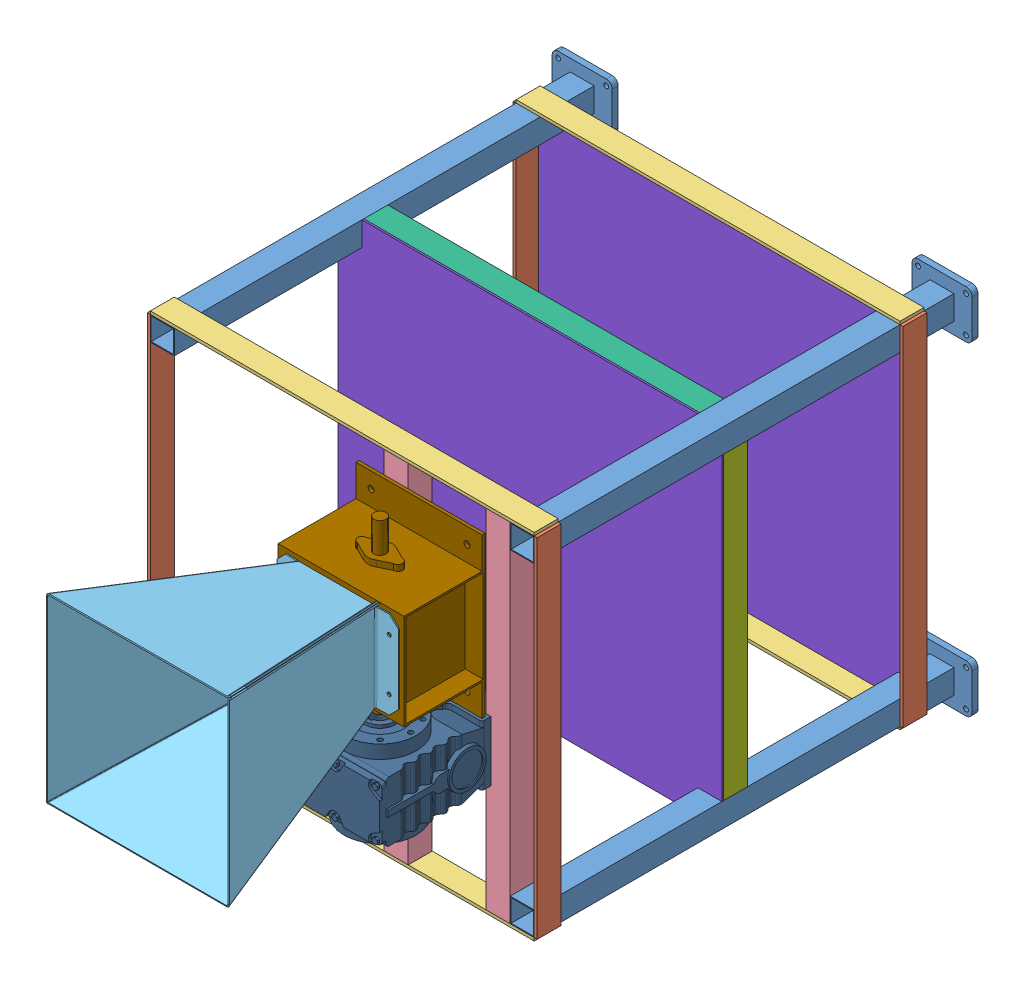
SolidWorks assembly Assemblage1, configuration Défaut. Lengths in mm.
Overall size (700 635.38 1223.8).
25 component instances, 10 part files, 63 mates.
Components (placement in the parent):
- PIED-1: PIED [Défaut] at (-115.1422 36.712 1420) x (-1 0 0) z (0 0 -1) size (100 80 710)
- PIED-2: PIED [Défaut] at (484.8578 36.712 1420) x (-1 0 0) z (0 0 -1) size (100 80 710)
- PIED-3: PIED [Défaut] at (-115.1422 -503.288 1420) x (-1 0 0) z (0 0 -1) size (100 80 710)
- PIED-4: PIED [Défaut] at (484.8578 -503.288 1420) x (-1 0 0) z (0 0 -1) size (100 80 710)
- RENFORT_largeur-1: RENFORT_largeur [Défaut] at (509.8578 -233.288 790) x (0 1 0) z (-1 0 0) size (580 40 5)
- RENFORT_largeur-2: RENFORT_largeur [Défaut] at (509.8578 -233.288 1400) x (0 1 0) z (-1 0 0) size (580 40 5)
- RENFORT_largeur-3: RENFORT_largeur [Défaut] at (-140.1422 -233.288 790) x (0 -1 0) z (1 0 0) size (580 40 5)
- RENFORT_largeur-4: RENFORT_largeur [Défaut] at (-140.1422 -233.288 1400) x (0 -1 0) z (1 0 0) size (580 40 5)
- RENFORT_longueur-1: RENFORT_longueur [Défaut] at (184.8578 61.712 790) x (1 0 0) z (0 -1 0) size (640 40 5)
- RENFORT_longueur-2: RENFORT_longueur [Défaut] at (184.8578 61.712 1400) x (1 0 0) z (0 -1 0) size (640 40 5)
- RENFORT_longueur-3: RENFORT_longueur [Défaut] at (184.8578 -528.288 790) x (1 0 0) z (0 1 0) size (640 40 5)
- RENFORT_longueur-4: RENFORT_longueur [Défaut] at (184.8578 -528.288 1400) x (1 0 0) z (0 1 0) size (640 40 5)
- 580mm 40x40-1: 580mm 40x40 [Défaut] at (274.8578 -523.288 1400) x (0 0 1) z (0 1 0) size (40 40 580)
- 580mm 40x40-2: 580mm 40x40 [Défaut] at (444.8578 -523.288 1400) x (-1 0 0) z (0 1 0) size (40 40 580)
- Trémie Assemblée-1: Trémie Assemblée [Default] at (161.1073 -328.8776 1561.0107) x (0.999994 -0.00237 -0.00261) z (0.002608 -0.000629 0.999996) size (322.31 323.64 336.67)
  - Trémie-1: Trémie [Défaut] at (196.1744 257.0221 41.9114) size (320.13 321.45 336.3)
  - Trémie-2: Trémie [Défaut] at (192.2926 260.8978 41.7629) x (-0.999997 -0.00237 -0.000538) z (-0.000539 0.000628 1) size (320.13 321.45 336.3)
- 560mm 40x40-1: 560mm 40x40 [Défaut] at (-95.1422 -503.288 1083.9985) x (0 0 -1) z (1 0 0) size (40 40 560)
- 560mm 40x40-2: 560mm 40x40 [Défaut] at (-95.1422 36.712 1083.9985) x (0 0 -1) z (1 0 0) size (40 40 560)
- 500mm 40x40-1: 500mm 40x40 [Défaut] at (484.8578 -483.288 1083.9985) x (1 0 0) z (0 1 0) size (40 40 500)
- 500mm 40x40-2: 500mm 40x40 [Défaut] at (-115.1422 16.712 1083.9985) x (1 0 0) z (0 -1 0) size (40 40 500)
- WorkbenchV-1: WorkbenchV [Défaut] at (254.8578 -243.288 770) x (0 1 0) z (0 0 1) size (580 640 3)
- WorkbenchV-2: WorkbenchV [Défaut] at (114.8578 -223.288 1103.9985) x (0 -1 0) z (0 0 1) size (580 640 3)
- Shredder-2: Shredder [Défaut] at (359.8578 -70.788 1597) x (0 1 0) z (0 0 -1) size (280 210 135)
- SEW SA57DZ71C4-2: SEW SA57DZ71C4 [Défaut] at (359.8578 -217.9826 1532) x (-1 0 0) z (0 0 1) size (393.09 196.49 188.11)
Mates (geometry in assembly coordinates):
- Coïncidente1: coincident aligned: plane of PIED-1 through (-75.1422 6.712 710) normal (0 0 -1); plane of PIED-3 through (-75.1422 -533.288 710) normal (0 0 -1)
- Coïncidente2: coincident aligned: plane of PIED-1 through (-75.1422 6.712 710) normal (0 0 -1); plane of PIED-4 through (524.8578 -533.288 710) normal (0 0 -1)
- Coïncidente4: coincident aligned: plane of PIED-2 through (524.8578 6.712 710) normal (0 0 -1); plane of PIED-4 through (524.8578 -533.288 710) normal (0 0 -1)
- Coïncidente5: coincident anti-aligned: plane of PIED-3 through (-95.1422 -523.288 720) normal (0 -1 0); plane of RENFORT_longueur-4 through (184.8578 -523.288 1400) normal (0 1 0)
- Coïncidente6: coincident: plane of PIED-4 through (504.8578 -523.288 720) normal (1 0 0); line of RENFORT_longueur-4 through (504.8578 -523.288 1420) axis (0 0 -1)
- Coïncidente7: coincident aligned: plane of PIED-3 through (-95.1422 -523.288 720) normal (0 -1 0); plane of PIED-4 through (504.8578 -523.288 720) normal (0 -1 0)
- Coïncidente8: coincident aligned: plane of PIED-3 through (-135.1422 -523.288 720) normal (-1 0 0); plane of RENFORT_longueur-4 through (-135.1422 -523.288 1420) normal (-1 0 0)
- Coïncidente9: coincident anti-aligned: plane of PIED-3 through (-95.1422 -523.288 720) normal (0 -1 0); plane of RENFORT_longueur-3 through (184.8578 -523.288 790) normal (0 1 0)
- Coïncidente10: coincident: plane of PIED-4 through (504.8578 -523.288 720) normal (1 0 0); line of RENFORT_longueur-3 through (504.8578 -523.288 810) axis (0 0 -1)
- Coïncidente11: coincident aligned: plane of PIED-4 through (484.8578 -503.288 1420) normal (0 0 1); plane of RENFORT_longueur-4 through (-135.1422 -523.288 1420) normal (0 0 1)
- Distance1: distance = 50 mm anti-aligned: plane of PIED-4 through (524.8578 -533.288 720) normal (0 0 1); plane of RENFORT_longueur-3 through (-135.1422 -523.288 770) normal (0 0 -1)
- Coïncidente13: coincident anti-aligned: plane of PIED-2 through (504.8578 56.712 720) normal (0 1 0); plane of RENFORT_longueur-1 through (184.8578 56.712 790) normal (0 -1 0)
- Coïncidente14: coincident anti-aligned: plane of PIED-2 through (504.8578 56.712 720) normal (0 1 0); plane of RENFORT_longueur-2 through (184.8578 56.712 1400) normal (0 -1 0)
- Coïncidente15: coincident aligned: plane of PIED-2 through (504.8578 16.712 720) normal (1 0 0); plane of RENFORT_longueur-2 through (504.8578 56.712 1380) normal (1 0 0)
- Coïncidente16: coincident aligned: plane of PIED-2 through (504.8578 16.712 720) normal (1 0 0); plane of RENFORT_longueur-1 through (504.8578 56.712 770) normal (1 0 0)
- Coïncidente17: coincident aligned: plane of PIED-2 through (504.8578 16.712 720) normal (1 0 0); plane of PIED-4 through (504.8578 -523.288 720) normal (1 0 0)
- Coïncidente18: coincident: plane of PIED-1 through (-135.1422 16.712 720) normal (-1 0 0); line of PIED-3 through (-135.1422 -523.288 720) axis (0 0 1)
- Coïncidente19: coincident aligned: plane of RENFORT_longueur-1 through (-135.1422 56.712 810) normal (0 0 1); plane of RENFORT_longueur-3 through (-135.1422 -523.288 810) normal (0 0 1)
- Coïncidente20: coincident: plane of PIED-2 through (484.8578 36.712 1420) normal (0 0 1); line of RENFORT_longueur-2 through (504.8578 61.712 1420) axis (-1 0 0)
- Coïncidente21: coincident anti-aligned: plane of PIED-1 through (-95.1422 56.712 720) normal (0 1 0); plane of RENFORT_longueur-2 through (184.8578 56.712 1400) normal (0 -1 0)
- Coïncidente22: coincident anti-aligned: plane of PIED-1 through (-135.1422 16.712 720) normal (-1 0 0); plane of RENFORT_largeur-3 through (-135.1422 -233.288 790) normal (1 0 0)
- Coïncidente23: coincident aligned: plane of PIED-1 through (-95.1422 56.712 720) normal (0 1 0); plane of RENFORT_largeur-3 through (-135.1422 56.712 810) normal (0 1 0)
- Distance2: distance = 50 mm anti-aligned: plane of RENFORT_largeur-3 through (-135.1422 56.712 770) normal (0 0 -1); plane of PIED-1 through (-75.1422 6.712 720) normal (0 0 1)
- Coïncidente25: coincident aligned: plane of PIED-3 through (-95.1422 -523.288 720) normal (0 -1 0); plane of RENFORT_largeur-3 through (-135.1422 -523.288 810) normal (0 -1 0)
- Coïncidente26: coincident anti-aligned: plane of PIED-1 through (-135.1422 16.712 720) normal (-1 0 0); plane of RENFORT_largeur-4 through (-135.1422 -233.288 1400) normal (1 0 0)
- Coïncidente27: coincident aligned: plane of PIED-1 through (-115.1422 36.712 1420) normal (0 0 1); plane of RENFORT_largeur-4 through (-135.1422 56.712 1420) normal (0 0 1)
- Coïncidente28: coincident aligned: plane of PIED-2 through (504.8578 56.712 720) normal (0 1 0); plane of RENFORT_largeur-4 through (-135.1422 56.712 1420) normal (0 1 0)
- Coïncidente29: coincident anti-aligned: plane of PIED-2 through (504.8578 16.712 720) normal (1 0 0); plane of RENFORT_largeur-2 through (504.8578 -233.288 1400) normal (-1 0 0)
- Coïncidente30: coincident: line of RENFORT_largeur-2 through (509.8578 -523.288 1420) axis (0 1 0); plane of RENFORT_longueur-4 through (-135.1422 -523.288 1420) normal (0 0 1)
- Coïncidente31: coincident: point of PIED-4; moEndPointRef_w of RENFORT_largeur-2
- Coïncidente32: coincident anti-aligned: plane of PIED-4 through (504.8578 -523.288 720) normal (1 0 0); plane of RENFORT_largeur-1 through (504.8578 -233.288 790) normal (-1 0 0)
- Coïncidente33: coincident: line of RENFORT_largeur-1 through (504.8578 -523.288 810) axis (0 1 0); plane of RENFORT_longueur-3 through (-135.1422 -523.288 810) normal (0 0 1)
- Coïncidente34: coincident aligned: plane of PIED-4 through (504.8578 -523.288 720) normal (0 -1 0); plane of RENFORT_largeur-1 through (504.8578 -523.288 810) normal (0 -1 0)
- Coïncidente41: coincident aligned: plane of RENFORT_longueur-4 through (-135.1422 -523.288 1420) normal (0 0 1); plane of 580mm 40x40-1 through (254.8578 56.712 1420) normal (0 0 1)
- Coïncidente42: coincident anti-aligned: plane of RENFORT_longueur-4 through (184.8578 -523.288 1400) normal (0 1 0); plane of 580mm 40x40-1 through (274.8578 -523.288 1400) normal (0 -1 0)
- Coïncidente51: coincident anti-aligned: plane of RENFORT_longueur-2 through (184.8578 56.712 1400) normal (0 -1 0); plane of 580mm 40x40-2 through (444.8578 56.712 1400) normal (0 1 0)
- Coïncidente69: coincident aligned: plane of PIED-3 through (-95.1422 -523.288 720) normal (0 -1 0); plane of 560mm 40x40-1 through (464.8578 -523.288 1103.9985) normal (0 -1 0)
- Coïncidente71: coincident anti-aligned: plane of PIED-3 through (-95.1422 -523.288 720) normal (1 0 0); plane of 560mm 40x40-1 through (-95.1422 -503.288 1083.9985) normal (-1 0 0)
- Coïncidente72: coincident aligned: plane of PIED-1 through (-95.1422 16.712 720) normal (0 -1 0); plane of 560mm 40x40-2 through (464.8578 16.712 1103.9985) normal (0 -1 0)
- Coïncidente73: coincident aligned: plane of PIED-1 through (-95.1422 16.712 720) normal (0 -1 0); plane of 560mm 40x40-2 through (464.8578 16.712 1103.9985) normal (0 -1 0)
- Coïncidente75: coincident aligned: plane of PIED-1 through (-95.1422 16.712 720) normal (0 -1 0); plane of 560mm 40x40-2 through (464.8578 16.712 1103.9985) normal (0 -1 0)
- Coïncidente77: coincident anti-aligned: line of PIED-1 through (-95.1422 16.712 720) axis (0 0 1); line of 560mm 40x40-2 through (-95.1422 16.712 1103.9985) axis (0 0 -1)
- Coïncidente78: coincident aligned: plane of 560mm 40x40-1 through (464.8578 -523.288 1103.9985) normal (0 0 1); plane of 560mm 40x40-2 through (464.8578 16.712 1103.9985) normal (0 0 1)
- Coïncidente79: coincident anti-aligned: line of PIED-2 through (464.8578 16.712 1420) axis (0 1 0); line of 580mm 40x40-2 through (464.8578 56.712 1420) axis (0 -1 0)
- Coïncidente81: coincident aligned: plane of PIED-4 through (504.8578 -523.288 720) normal (1 0 0); plane of 500mm 40x40-1 through (504.8578 16.712 1103.9985) normal (1 0 0)
- Coïncidente82: coincident: line of PIED-2 through (504.8578 16.712 720) axis (0 0 1); unknown of 500mm 40x40-1
- Coïncidente83: coincident aligned: plane of 560mm 40x40-2 through (464.8578 16.712 1103.9985) normal (0 0 1); plane of 500mm 40x40-1 through (464.8578 16.712 1103.9985) normal (0 0 1)
- Coïncidente84: coincident aligned: plane of PIED-3 through (-135.1422 -523.288 720) normal (-1 0 0); plane of 500mm 40x40-2 through (-135.1422 -483.288 1063.9985) normal (-1 0 0)
- Coïncidente85: coincident aligned: plane of 560mm 40x40-2 through (464.8578 16.712 1103.9985) normal (0 0 1); plane of 500mm 40x40-2 through (-135.1422 -483.288 1103.9985) normal (0 0 1)
- Coïncidente86: coincident anti-aligned: plane of PIED-3 through (-95.1422 -483.288 720) normal (0 1 0); plane of 500mm 40x40-2 through (-115.1422 -483.288 1083.9985) normal (0 -1 0)
- Coïncidente94: coincident aligned: plane of RENFORT_largeur-3 through (-135.1422 56.712 770) normal (0 0 -1); plane of WorkbenchV-1 through (254.8578 -243.288 770) normal (0 0 -1)
- Coïncidente95: coincident: plane of PIED-3 through (-95.1422 -483.288 720) normal (0 1 0); line of WorkbenchV-1 through (-135.1422 -483.288 770) axis (1 0 0)
- Coïncidente96: coincident aligned: plane of PIED-3 through (-135.1422 -523.288 720) normal (-1 0 0); plane of WorkbenchV-1 through (-135.1422 -483.288 773) normal (-1 0 0)
- Coïncidente97: coincident anti-aligned: plane of 560mm 40x40-2 through (464.8578 16.712 1103.9985) normal (0 0 1); plane of WorkbenchV-2 through (114.8578 -223.288 1103.9985) normal (0 0 -1)
- Coïncidente100: coincident aligned: plane of 560mm 40x40-2 through (464.8578 56.712 1103.9985) normal (0 1 0); plane of WorkbenchV-2 through (-95.1422 56.712 1106.9985) normal (0 1 0)
- Coïncidente101: coincident aligned: plane of 500mm 40x40-2 through (-135.1422 -483.288 1063.9985) normal (-1 0 0); plane of WorkbenchV-2 through (-135.1422 16.712 1106.9985) normal (-1 0 0)
- Coïncidente107: coincident aligned: plane of RENFORT_longueur-2 through (-135.1422 56.712 1420) normal (0 0 1); plane of 580mm 40x40-2 through (464.8578 56.712 1420) normal (0 0 1)
- Coïncidente108: coincident aligned: plane of 580mm 40x40-1 through (254.8578 56.712 1380) normal (-1 0 0); plane of Shredder-2 through (254.8578 -150.788 1462) normal (-1 0 0)
- Coïncidente110: coincident aligned: plane of 580mm 40x40-2 through (464.8578 56.712 1380) normal (1 0 0); plane of Shredder-2 through (464.8578 -150.788 1462) normal (1 0 0)
- Coïncidente111: coincident aligned: plane of RENFORT_longueur-2 through (184.8578 61.712 1400) normal (0 1 0); plane of Shredder-2 through (254.8578 61.712 1467) normal (0 1 0)
- Coaxiale4: concentric aligned: cylinder of Shredder-2 through (359.8578 -210.788 1532) axis (0 1 0) radius 10; cone of SEW SA57DZ71C4-2 through (359.8578 -281.9826 1532) axis (0 1 0)
- Coïncidente112: coincident anti-aligned: plane of 580mm 40x40-1 through (254.8578 56.712 1420) normal (0 0 1); plane of SEW SA57DZ71C4-2 through (434.8578 -289.9826 1420) normal (0 0 -1)
- Coïncidente114: coincident aligned: line of Trémie Assemblée-1/Trémie-2 through (254.8578 -128.4625 1597) axis (0 1 0); line of Shredder-2 through (254.8578 -150.788 1597) axis (0 1 0)
